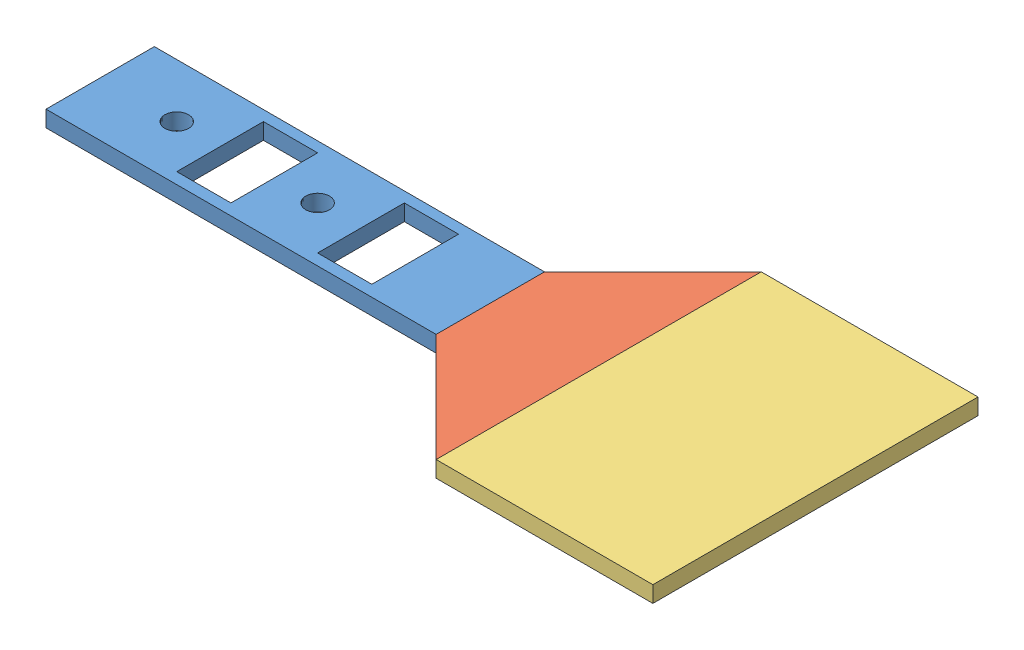
SolidWorks assembly Total, configuration Default. Lengths in mm.
Overall size (66 1.5 30).
3 component instances, 3 part files, 2 mates.
Components (placement in the parent):
- P1-1: P1 [Default] at (11.2531 17.6456 29.0517) size (36 1.5 10)
- P3-1: P3 [Default] at (39.2531 17.6456 29.0517) size (10 1.5 30)
- P2-1: P2 [Default] at (49.2531 17.6456 29.0517) size (20 1.5 30)
Mates (geometry in assembly coordinates):
- Coincident1: coincident: point of P1-1; point of P3-1
- Coincident2: coincident: point of P3-1; point of P2-1
